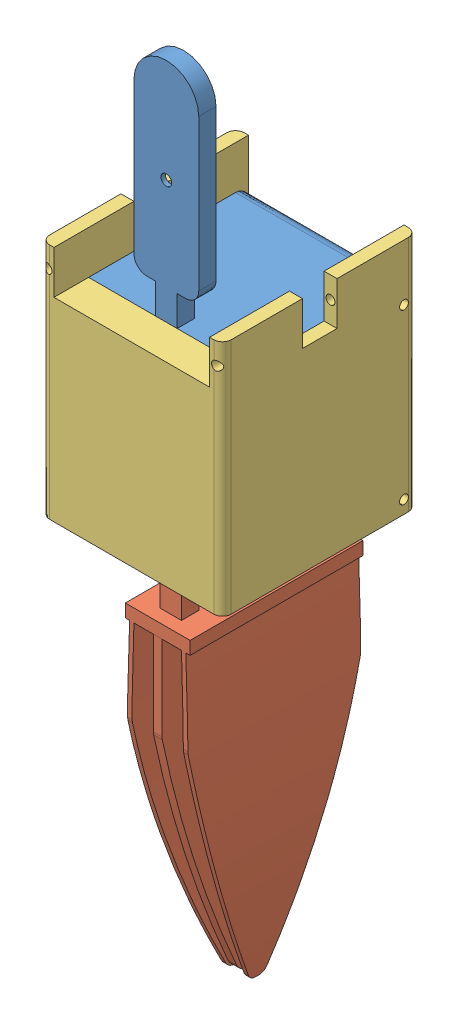
SolidWorks assembly test1, configuration 預設. Lengths in mm.
Overall size (42 193.5 52.29).
3 component instances, 3 part files, 5 mates.
Components (placement in the parent):
- little_connect2-1: little_connect2 [預設] at (-8.1298 -4.4128 97.5) size (36 97.5 37)
- littletail2-1: littletail2 [預設] at (-7.1298 -60.414 99.5) size (19.67 137.5 41.71)
- little_connect_part2_3_final-1: little_connect_part2_3_final [預設] at (-13.5844 -22.5037 104.5) x (1 0 0) z (0 0 -1) size (42 55 50.58)
Mates (geometry in assembly coordinates):
- 重合/共線/共點1: coincident: plane of little_connect2-1 through (-8.1298 50.5872 101.5) normal (0 0 1); plane of littletail2-1 through (-7.1298 -5.414 101.5) normal (0 0 1)
- 重合/共線/共點2: coincident: line of little_connect2-1 through (-14.6298 -9.4128 83.5) axis (0 -1 0); plane of littletail2-1 through (-14.6298 -52.414 97.5) normal (-1 0 0)
- 同軸心3: concentric: cylinder of little_connect2-1 through (-21.1298 2.5872 67.5) axis (-1 0 0) radius 1.025; cylinder of little_connect_part2_3_final-1 through (16.3702 2.5872 67.5) axis (-1 0 0) radius 1.025
- 同軸心4: concentric: cylinder of little_connect2-1 through (-21.1298 -36.4128 67.5) axis (-1 0 0) radius 1.025; cylinder of little_connect_part2_3_final-1 through (16.3702 -36.4128 67.5) axis (-1 0 0) radius 1.025
- 重合/共線/共點4: coincident: plane of little_connect2-1 through (-26.1298 5.5872 64.5) normal (-1 0 0); plane of little_connect_part2_3_final-1 through (-26.1298 10.5872 101.5) normal (1 0 0)
